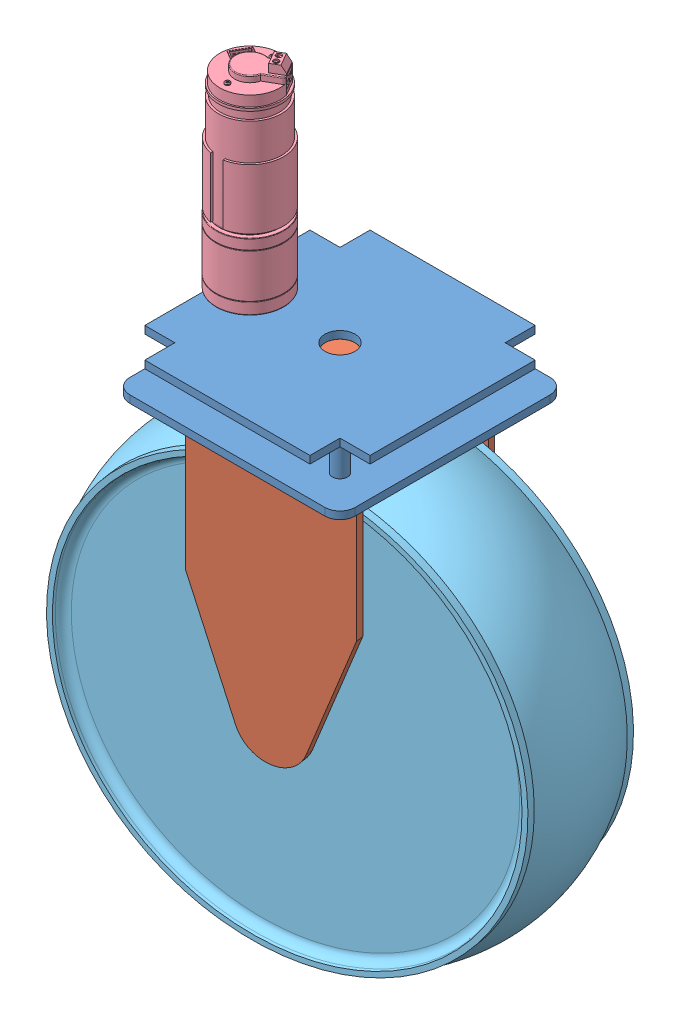
SolidWorks assembly swerve, configuration Default. Lengths in mm.
Overall size (414.42 529.69 150).
5 component instances, 5 part files, 13 mates.
Components (placement in the parent):
- dudukan_motor_swerve-1: dudukan_motor_swerve [Default] at origin size (150 30 150)
- dudukan_roda_swerve-2: dudukan_roda_swerve [Default] at (-8.3419 -160 -54.3637) x (0.988431 0 -0.15167) z (0.15167 0 0.988431) size (100 207 110)
- gear_motor_swerve-1: gear_motor_swerve [Default] at (-60 10 0) x (0.888807 0 0.458282) z (-0.458282 0 0.888807) size (24.59 20 24.53)
- Motor_PG457-1: Motor_PG457 [Default] at (-27.768 31.5 14.9868) x (1 0 0) z (0 1 0) size (45 45 162)
- roda-1: roda [Predeterminado] at (-6.2139 -160 -40.4956) x (-0.15167 0 -0.988431) z (0.852945 0.505327 -0.13088) size (84.02 297.01 297.01)
Mates (geometry in assembly coordinates):
- Coincident3: coordinate: point of Dudukan-1
- Parallel1: parallel aligned: plane of Dudukan-1 through (0 30 75) normal (0 0 1)
- Coincident4: coincident anti-aligned: plane of Dudukan-1 through (0 5 0) normal (0 1 0); plane of dudukan_roda_swerve-2 through (0 5 0) normal (0 -1 0)
- Concentric1: concentric aligned: cylinder of Dudukan-1 through (0 30 0) axis (0 -1 0) radius 10; cylinder of dudukan_roda_swerve-2 through (0 5 0) axis (0 -1 0) radius 10
- Coincident5: coincident anti-aligned: plane of Dudukan-1 through (0 5 0) normal (0 1 0); plane of gear_motor_swerve-1 through (-60 5 0) normal (0 -1 0)
- Concentric2: concentric aligned: cylinder of Dudukan-1 through (-60 -15 0) axis (0 1 0) radius 5.5; cylinder of gear_motor_swerve-1 through (-60 5 0) axis (0 1 0) radius 5
- GearMate1: gear = 20 : 5 mm: cylinder of gear_motor_swerve-1 through (-60 25 0) axis (0 -1 0) radius 7.5; cylinder of dudukan_roda_swerve-2 through (0 25 0) axis (0 -1 0) radius 10
- Coincident6: coincident anti-aligned: plane of Dudukan-1 through (0 30 0) normal (0 1 0); plane of PG457 DC Motor-1 through (-60 30 0) normal (0 -1 0)
- Concentric3: concentric anti-aligned: cylinder of Dudukan-1 through (-72.5511 25 -12.5511) axis (0 1 0) radius 2; cylinder of PG457 DC Motor-1 through (-72.5511 36.5 -12.5511) axis (0 -1 0) radius 2
- Concentric4: concentric anti-aligned: cylinder of Dudukan-1 through (-72.5511 25 12.5511) axis (0 1 0) radius 2; cylinder of PG457 DC Motor-1 through (-72.5511 36.5 12.5511) axis (0 -1 0) radius 2
- Width1: width anti-aligned: plane of roda-1 through (-74.1664 -42.8742 -31.1197) normal (-0.15167 0 -0.988431); plane of dudukan_roda_swerve-2 through (-63.8637 -38.6584 52.2998) normal (0.15167 0 0.988431); plane of roda-1 through (-7.5835 -160 -49.4216) normal (0.15167 0 0.988431); plane of dudukan_roda_swerve-2 through (7.5835 -160 49.4216) normal (-0.15167 0 -0.988431)
- Concentric5: concentric aligned: cylinder of dudukan_roda_swerve-2 through (-5.3085 -160 -34.5951) axis (-0.15167 0 -0.988431) radius 10; circle of Rueda-1
- GearMate2: gear = 20 : 4 mm: cylinder of gear_motor_swerve-1 through (-60 25 0) axis (0 -1 0) radius 7.5; cylinder of dudukan_roda_swerve-2 through (0 25 0) axis (0 -1 0) radius 10
